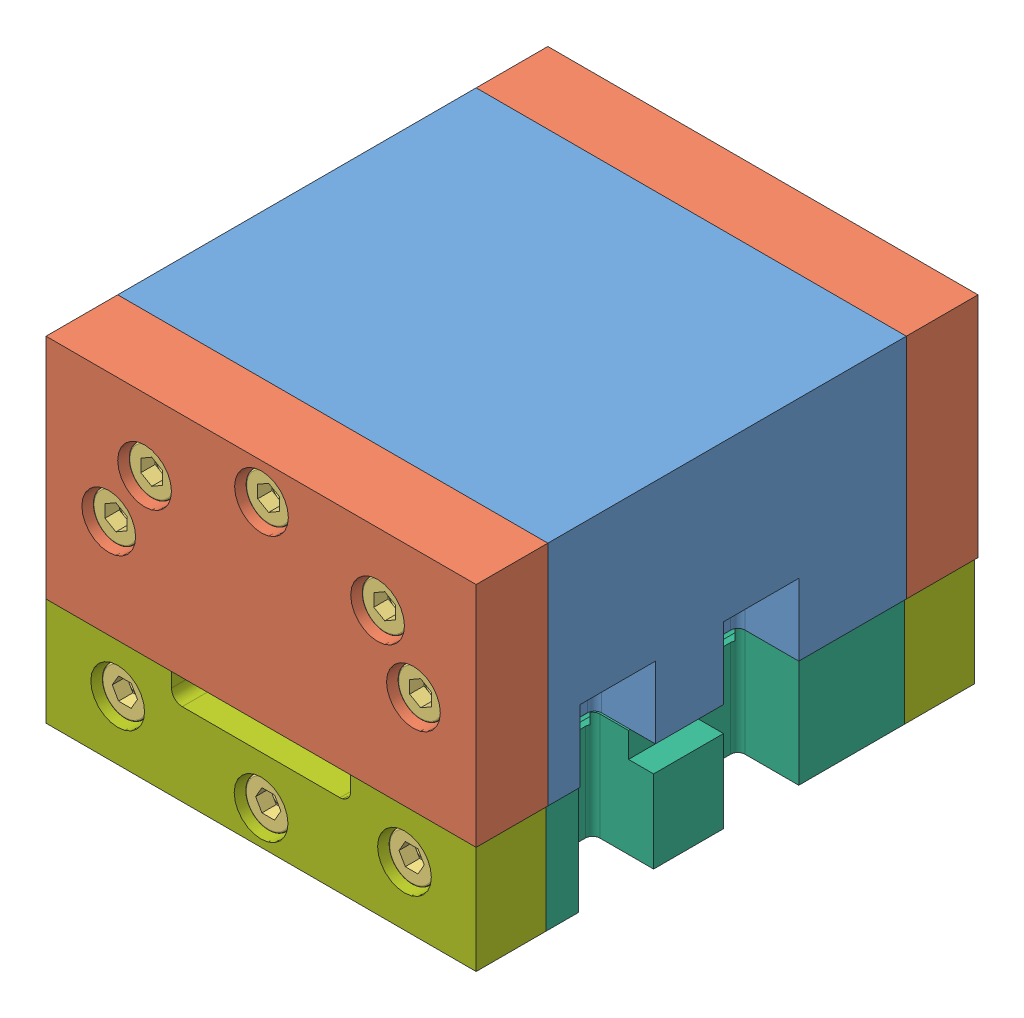
SolidWorks assembly Сборка, configuration По умолчанию. Lengths in mm.
Overall size (120 93.5 140).
27 component instances, 7 part files, 37 mates.
Components (placement in the parent):
- Матрица-1: Матрица [По умолчанию] at origin size (120 63.5 100)
- БоковинаПресс-формы-1: БоковинаПресс-формы [По умолчанию] at (0 63.5 0) x (0 0 -1) z (-1 0 0) size (20 63.5 120)
- БоковинаПресс-формы-2: БоковинаПресс-формы [По умолчанию] at (120 63.5 100) x (0 0 1) z (1 0 0) size (20 63.5 120)
- socket head cap screw_iso-1: socket head cap screw_iso [ISO 4762 M8 x 16 - 16N] at (17.5 27.5 118) x (0 0 -1) z (1 0 0) size (24 13 13)
- socket head cap screw_iso-2: socket head cap screw_iso [ISO 4762 M8 x 16 - 16N] at (27.5 43.5 118) x (0 0 -1) z (1 0 0) size (24 13 13)
- socket head cap screw_iso-3: socket head cap screw_iso [ISO 4762 M8 x 16 - 16N] at (60.109 53.5 118) x (0 0 -1) z (1 0 0) size (24 13 13)
- socket head cap screw_iso-4: socket head cap screw_iso [ISO 4762 M8 x 16 - 16N] at (92.5 43.5 118) x (0 0 -1) z (1 0 0) size (24 13 13)
- socket head cap screw_iso-5: socket head cap screw_iso [ISO 4762 M8 x 16 - 16N] at (102.5 27.5 118) x (0 0 -1) z (1 0 0) size (24 13 13)
- socket head cap screw_iso-6: socket head cap screw_iso [ISO 4762 M8 x 16 - 16N] at (102.5 27.5 -18) x (0 0 1) z (-1 0 0) size (24 13 13)
- socket head cap screw_iso-7: socket head cap screw_iso [ISO 4762 M8 x 16 - 16N] at (92.5 43.5 -18) x (0 0 1) z (-1 0 0) size (24 13 13)
- socket head cap screw_iso-8: socket head cap screw_iso [ISO 4762 M8 x 16 - 16N] at (59.891 53.5 -18) x (0 0 1) z (-1 0 0) size (24 13 13)
- socket head cap screw_iso-9: socket head cap screw_iso [ISO 4762 M8 x 16 - 16N] at (27.5 43.5 -18) x (0 0 1) z (-1 0 0) size (24 13 13)
- socket head cap screw_iso-10: socket head cap screw_iso [ISO 4762 M8 x 16 - 16N] at (17.5 27.5 -18) x (0 0 1) z (-1 0 0) size (24 13 13)
- Направляющая-2: Направляющая [По умолчанию] at (8 30 88) x (0 -1 0) z (0.779572 0 -0.626312) size (55 10 10)
- Направляющая-3: Направляющая [По умолчанию] at (112 30 13) x (0 -1 0) z (-0.854743 0 -0.519052) size (55 10 10)
- Подставка-1: Подставка [По умолчанию] at (60 33.5 77) x (0 -1 0) z (-0.902288 0 0.431134) size (36.5 13.89 13.89)
- Подставка-2: Подставка [По умолчанию] at (60 33.5 23) x (0 -1 0) z (-0.706159 0 0.708053) size (36.5 13.89 13.89)
- СборкаВерх-1: СборкаВерх [По умолчанию] at (0 0 100.5) x (1 0 0) z (0 1 0) size (120 139 30)
  - Пуансон-1: Пуансон [По умолчанию] at origin size (120 100 30)
  - БоковинаПуасона-1: БоковинаПуасона [По умолчанию] at (120 100 -30) x (-1 0 0) z (0 0 -1) size (120 19.5 30)
  - БоковинаПуасона-3: БоковинаПуасона [По умолчанию] at (0 0 -30) x (1 0 0) z (0 0 -1) size (120 19.5 30)
  - socket head cap screw_iso-1: socket head cap screw_iso [ISO 4762 M8 x 16 - 16N] at (100 -17.5 -13.5) x (0 1 0) z (0 0 1) size (24 13 13)
  - socket head cap screw_iso-2: socket head cap screw_iso [ISO 4762 M8 x 16 - 16N] at (60 -17.5 -20.5) x (0 1 0) z (0 0 1) size (24 13 13)
  - socket head cap screw_iso-3: socket head cap screw_iso [ISO 4762 M8 x 16 - 16N] at (20 -17.5 -13.5) x (0 1 0) z (0 0 1) size (24 13 13)
  - socket head cap screw_iso-4: socket head cap screw_iso [ISO 4762 M8 x 16 - 16N] at (20 117.5 -13.5) x (0 -1 0) z (0 0 1) size (24 13 13)
  - socket head cap screw_iso-5: socket head cap screw_iso [ISO 4762 M8 x 16 - 16N] at (60 117.5 -20.5) x (0 -1 0) z (0 0 1) size (24 13 13)
  - socket head cap screw_iso-6: socket head cap screw_iso [ISO 4762 M8 x 16 - 16N] at (100 117.5 -13.5) x (0 -1 0) z (0 0 1) size (24 13 13)
Mates (geometry in assembly coordinates):
- Совпадение1: coincident anti-aligned: plane of Матрица-1 through (0 0 0) normal (0 0 -1); plane of БоковинаПресс-формы-1 through (0 63.5 0) normal (0 0 1)
- Концентричный1: concentric aligned: cylinder of Матрица-1 through (92.5 43.5 30) axis (0 0 -1) radius 4; cylinder of БоковинаПресс-формы-1 through (92.5 43.5 0) axis (0 0 -1) radius 4.25
- Концентричный2: concentric aligned: cylinder of Матрица-1 through (27.5 43.5 30) axis (0 0 -1) radius 4; cylinder of БоковинаПресс-формы-1 through (27.5 43.5 0) axis (0 0 -1) radius 4.25
- Совпадение2: coincident anti-aligned: plane of Матрица-1 through (0 0 100) normal (0 0 1); plane of БоковинаПресс-формы-2 through (120 63.5 100) normal (0 0 -1)
- Концентричный4: concentric aligned: cylinder of Матрица-1 through (17.5 27.5 70) axis (0 0 1) radius 4; cylinder of БоковинаПресс-формы-2 through (17.5 27.5 100) axis (0 0 1) radius 4.25
- Концентричный5: concentric aligned: cylinder of Матрица-1 through (102.5 27.5 70) axis (0 0 1) radius 4; cylinder of БоковинаПресс-формы-2 through (102.5 27.5 100) axis (0 0 1) radius 4.25
- Концентричный6: concentric aligned: cylinder of БоковинаПресс-формы-2 through (17.5 27.5 100) axis (0 0 1) radius 4.25; cylinder of socket head cap screw_iso-1 through (17.5 27.5 149.75) axis (0 0 1) radius 6.5
- Совпадение3: coincident anti-aligned: plane of БоковинаПресс-формы-2 through (17.5 27.5 110) normal (0 0 1); plane of socket head cap screw_iso-1 through (17.5 34 110) normal (0 0 -1)
- Концентричный7: concentric aligned: cylinder of БоковинаПресс-формы-2 through (27.5 43.5 110) axis (0 0 1) radius 7.5; cylinder of socket head cap screw_iso-2 through (27.5 43.5 149.75) axis (0 0 1) radius 6.5
- Совпадение4: coincident anti-aligned: plane of БоковинаПресс-формы-2 through (27.5 43.5 110) normal (0 0 1); plane of socket head cap screw_iso-2 through (27.5 50 110) normal (0 0 -1)
- Концентричный8: concentric aligned: cylinder of БоковинаПресс-формы-2 through (60.109 53.5 100) axis (0 0 1) radius 4.25; cylinder of socket head cap screw_iso-3 through (60.109 53.5 149.75) axis (0 0 1) radius 6.5
- Совпадение5: coincident anti-aligned: plane of БоковинаПресс-формы-2 through (60.109 53.5 110) normal (0 0 1); plane of socket head cap screw_iso-3 through (60.109 60 110) normal (0 0 -1)
- Концентричный9: concentric aligned: cylinder of БоковинаПресс-формы-2 through (92.5 43.5 100) axis (0 0 1) radius 4.25; cylinder of socket head cap screw_iso-4 through (92.5 43.5 149.75) axis (0 0 1) radius 6.5
- Совпадение6: coincident anti-aligned: plane of БоковинаПресс-формы-2 through (92.5 43.5 110) normal (0 0 1); plane of socket head cap screw_iso-4 through (92.5 50 110) normal (0 0 -1)
- Концентричный10: concentric aligned: cylinder of БоковинаПресс-формы-2 through (102.5 27.5 100) axis (0 0 1) radius 4.25; cylinder of socket head cap screw_iso-5 through (102.5 27.5 149.75) axis (0 0 1) radius 6.5
- Совпадение7: coincident anti-aligned: plane of БоковинаПресс-формы-2 through (102.5 27.5 110) normal (0 0 1); plane of socket head cap screw_iso-5 through (102.5 34 110) normal (0 0 -1)
- Концентричный11: concentric aligned: cylinder of БоковинаПресс-формы-1 through (102.5 27.5 0) axis (0 0 -1) radius 4.25; cylinder of socket head cap screw_iso-6 through (102.5 27.5 -49.75) axis (0 0 -1) radius 6.5
- Совпадение8: coincident anti-aligned: plane of БоковинаПресс-формы-1 through (102.5 27.5 -10) normal (0 0 -1); plane of socket head cap screw_iso-6 through (102.5 34 -10) normal (0 0 1)
- Концентричный12: concentric aligned: cylinder of БоковинаПресс-формы-1 through (92.5 43.5 -10) axis (0 0 -1) radius 7.5; cylinder of socket head cap screw_iso-7 through (92.5 43.5 -49.75) axis (0 0 -1) radius 6.5
- Совпадение9: coincident anti-aligned: plane of БоковинаПресс-формы-1 through (92.5 43.5 -10) normal (0 0 -1); plane of socket head cap screw_iso-7 through (92.5 50 -10) normal (0 0 1)
- Концентричный13: concentric aligned: cylinder of БоковинаПресс-формы-1 through (59.891 53.5 0) axis (0 0 -1) radius 4.25; cylinder of socket head cap screw_iso-8 through (59.891 53.5 -49.75) axis (0 0 -1) radius 6.5
- Совпадение10: coincident anti-aligned: plane of БоковинаПресс-формы-1 through (59.891 53.5 -10) normal (0 0 -1); plane of socket head cap screw_iso-8 through (59.891 60 -10) normal (0 0 1)
- Концентричный14: concentric aligned: cylinder of БоковинаПресс-формы-1 through (27.5 43.5 0) axis (0 0 -1) radius 4.25; cylinder of socket head cap screw_iso-9 through (27.5 43.5 -49.75) axis (0 0 -1) radius 6.5
- Совпадение11: coincident anti-aligned: plane of БоковинаПресс-формы-1 through (27.5 43.5 -10) normal (0 0 -1); plane of socket head cap screw_iso-9 through (27.5 50 -10) normal (0 0 1)
- Концентричный15: concentric aligned: cylinder of БоковинаПресс-формы-1 through (17.5 27.5 -10) axis (0 0 -1) radius 7.5; cylinder of socket head cap screw_iso-10 through (17.5 27.5 -49.75) axis (0 0 -1) radius 6.5
- Совпадение12: coincident anti-aligned: plane of БоковинаПресс-формы-1 through (17.5 27.5 -10) normal (0 0 -1); plane of socket head cap screw_iso-10 through (17.5 34 -10) normal (0 0 1)
- Концентричный18: concentric anti-aligned: cylinder of Матрица-1 through (8 30 88) axis (0 -1 0) radius 5; cylinder of Направляющая-2 through (8 30 88) axis (0 1 0) radius 5
- Совпадение13: coincident anti-aligned: plane of Матрица-1 through (8 30 88) normal (0 -1 0); plane of Направляющая-2 through (8 30 88) normal (0 1 0)
- Концентричный19: concentric anti-aligned: cylinder of Матрица-1 through (112 30 13) axis (0 -1 0) radius 5; cylinder of Направляющая-3 through (112 30 13) axis (0 1 0) radius 5
- Совпадение14: coincident anti-aligned: plane of Матрица-1 through (112 30 13) normal (0 -1 0); plane of Направляющая-3 through (112 30 13) normal (0 1 0)
- Концентричный20: concentric anti-aligned: cylinder of Матрица-1 through (60 33.5 77) axis (0 -1 0) radius 6; cylinder of Подставка-1 through (60 33.5 77) axis (0 1 0) radius 6.9453
- Концентричный21: concentric anti-aligned: cylinder of Матрица-1 through (60 33.5 23) axis (0 -1 0) radius 6; cylinder of Подставка-2 through (60 33.5 23) axis (0 1 0) radius 6.9453
- Совпадение16: coincident anti-aligned: plane of Матрица-1 through (60 33.5 23) normal (0 -1 0); plane of Подставка-2 through (60 33.5 23) normal (0 1 0)
- Совпадение18: coincident aligned: plane of Подставка-1 through (63.6092 -3 75.2755) normal (0 -1 0); plane of Подставка-2 through (62.8246 -3 20.1678) normal (0 -1 0)
- Концентричный22: concentric aligned: cylinder of Направляющая-3 through (112 30 13) axis (0 1 0) radius 5; cylinder of СборкаВерх-1/Пуансон-1 through (112 -30 13) axis (0 1 0) radius 5
- Концентричный23: concentric aligned: cylinder of Направляющая-2 through (8 30 88) axis (0 1 0) radius 5; cylinder of СборкаВерх-1/Пуансон-1 through (8 -30 88) axis (0 1 0) radius 5
- Граничное расстояние1: limit distance = 0 mm anti-aligned: plane of БоковинаПресс-формы-2 through (120 0 120) normal (0 -1 0); plane of СборкаВерх-1/БоковинаПуасона-3 through (0 0 120) normal (0 1 0)
